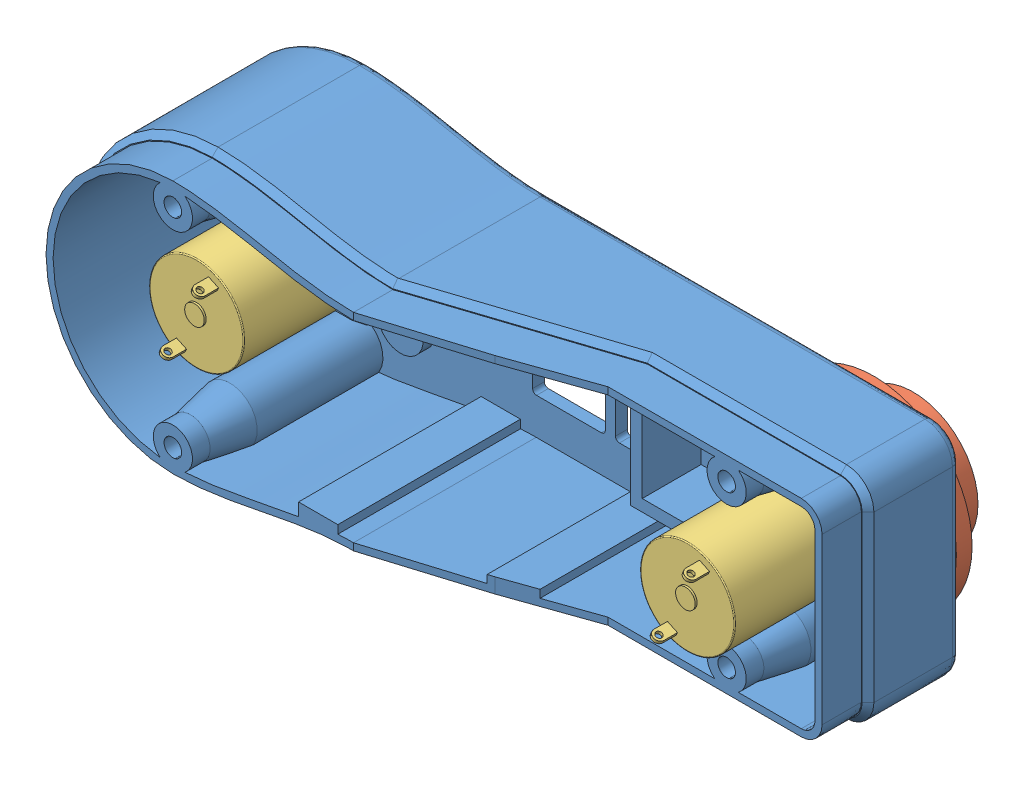
SolidWorks assembly Side_Assem_Right, configuration Default. Lengths in mm.
Overall size (185 73.69 73).
5 component instances, 3 part files, 10 mates.
Components (placement in the parent):
- Side_Right-1: Side_Right [Default] at (-39.1233 1.1983 -96.7118) size (185 73.69 50.44)
- motor_holder_r0.4-1: motor_holder_r0.4 [Default] at (-100.1233 1.1983 -96.7118) x (0 0 -1) z (1 0 0) size (14 50 50)
- Motor_25x55_gear-1: Motor_25x55_gear [Default] at (-100.1233 1.1983 -106.2118) x (0.420697 0.907201 0) z (0 0 -1) size (25 25 71.85)
- Motor_25x55_gear-2: Motor_25x55_gear [Default] at (24.8767 1.1983 -106.2118) x (0.420697 0.907201 0) z (0 0 -1) size (25 25 71.85)
- motor_holder_r0.4-2: motor_holder_r0.4 [Default] at (24.8767 1.1983 -96.7118) x (0 0 -1) z (1 0 0) size (14 50 50)
Mates (geometry in assembly coordinates):
- Concentric1: concentric anti-aligned: cylinder of motor_holder_r0.4-1 through (-100.1233 1.1983 -110.7118) axis (0 0 1) radius 16.5; cylinder of Motor_25x55_gear-1 through (-100.1233 1.1983 -85.2118) axis (0 0 -1) radius 12.5
- Coincident1: coincident anti-aligned: circle of motor_holder_r0.4-1; plane of Motor_25x55_gear-1 through (-100.1233 1.1983 -108.2118) normal (0 0 -1)
- Concentric2: concentric aligned: cylinder of Side_Right-1 through (24.8767 1.1983 -37.2118) axis (0 0 -1) radius 13; cylinder of Motor_25x55_gear-2 through (24.8767 1.1983 -53.2118) axis (0 0 -1) radius 12.05
- Concentric3: concentric aligned: cylinder of Side_Right-1 through (-100.1233 1.1983 -37.2118) axis (0 0 -1) radius 13; cylinder of Motor_25x55_gear-1 through (-100.1233 1.1983 -53.2118) axis (0 0 -1) radius 12.05
- Coincident2: coincident anti-aligned: plane of Side_Right-1 through (-39.1233 1.1983 -96.7118) normal (0 0 -1); plane of motor_holder_r0.4-2 through (24.8767 1.1983 -96.7118) normal (0 0 1)
- Coincident3: coincident anti-aligned: plane of Side_Right-1 through (-39.1233 1.1983 -96.7118) normal (0 0 -1); plane of motor_holder_r0.4-1 through (-100.1233 1.1983 -96.7118) normal (0 0 1)
- Coincident5: coincident anti-aligned: plane of Motor_25x55_gear-2 through (24.8767 1.1983 -108.2118) normal (0 0 -1); plane of motor_holder_r0.4-2 through (24.8767 1.1983 -108.2118) normal (0 0 1)
- Concentric4: concentric aligned: circle of Motor_25x55_gear-2; cylinder of motor_holder_r0.4-2 through (24.8767 1.1983 -145.3349) axis (0 0 1) radius 13.125
- Concentric5: concentric aligned: cylinder of Side_Right-1 through (10.381 15.694 -37.2118) axis (0 0 -1) radius 1.25; cylinder of motor_holder_r0.4-2 through (10.381 15.694 -100.7118) axis (0 0 -1) radius 1.7
- Concentric6: concentric aligned: cylinder of Side_Right-1 through (39.3724 -13.2974 -37.2118) axis (0 0 -1) radius 1.25; cylinder of motor_holder_r0.4-2 through (39.3724 -13.2974 -100.7118) axis (0 0 -1) radius 1.7
